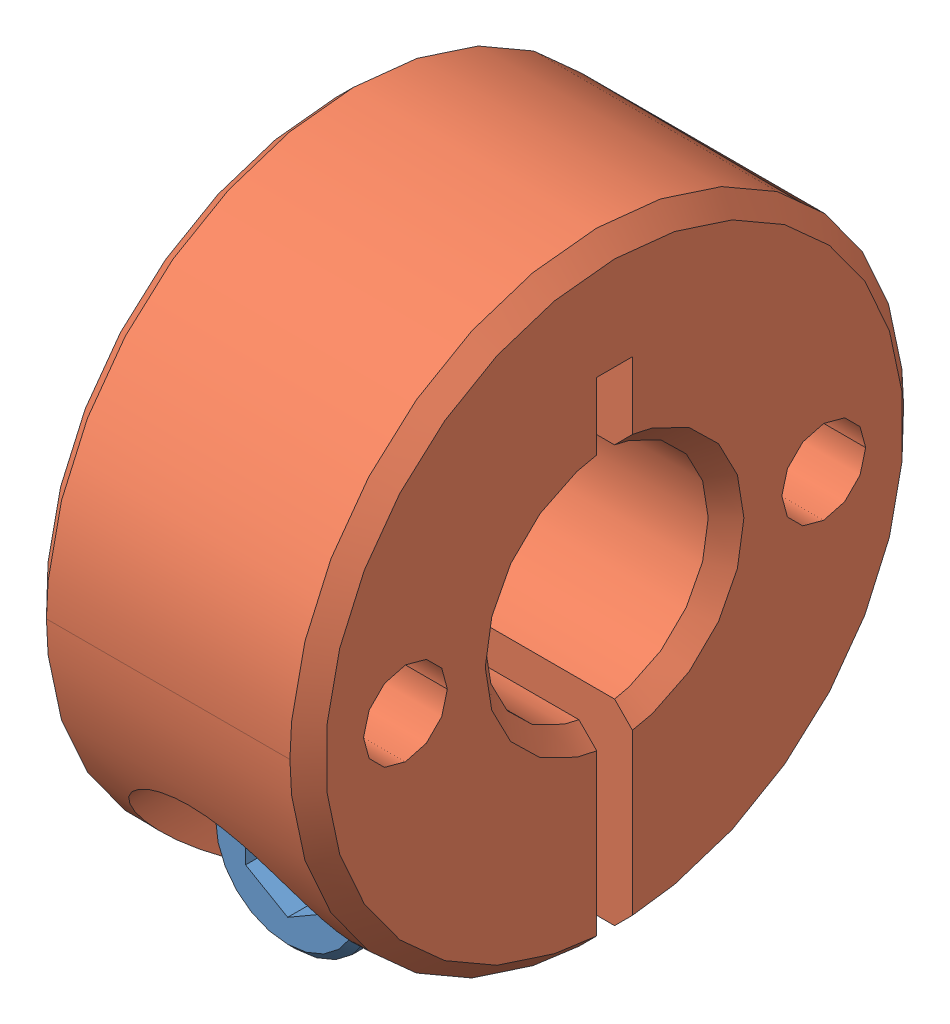
SolidWorks assembly U_SCSM0_25_B0_31, configuration U-SCSW0.25-B0.31. Lengths in mm.
Overall size (7.95 17.48 17.48).
2 component instances, 2 part files, 0 mates.
Components (placement in the parent):
- U_SCSM0_25_B0_31_3-1: U_SCSM0_25_B0_31_3 [Default] at (0 -5.9436 2.54) x (0 0 -1) z (-1 0 0) size (9.14 4.56 4.56)
- U_SCSM0_25_B0_31_5-1: U_SCSM0_25_B0_31_5 [Default] at origin size (7.95 17.48 17.48)
